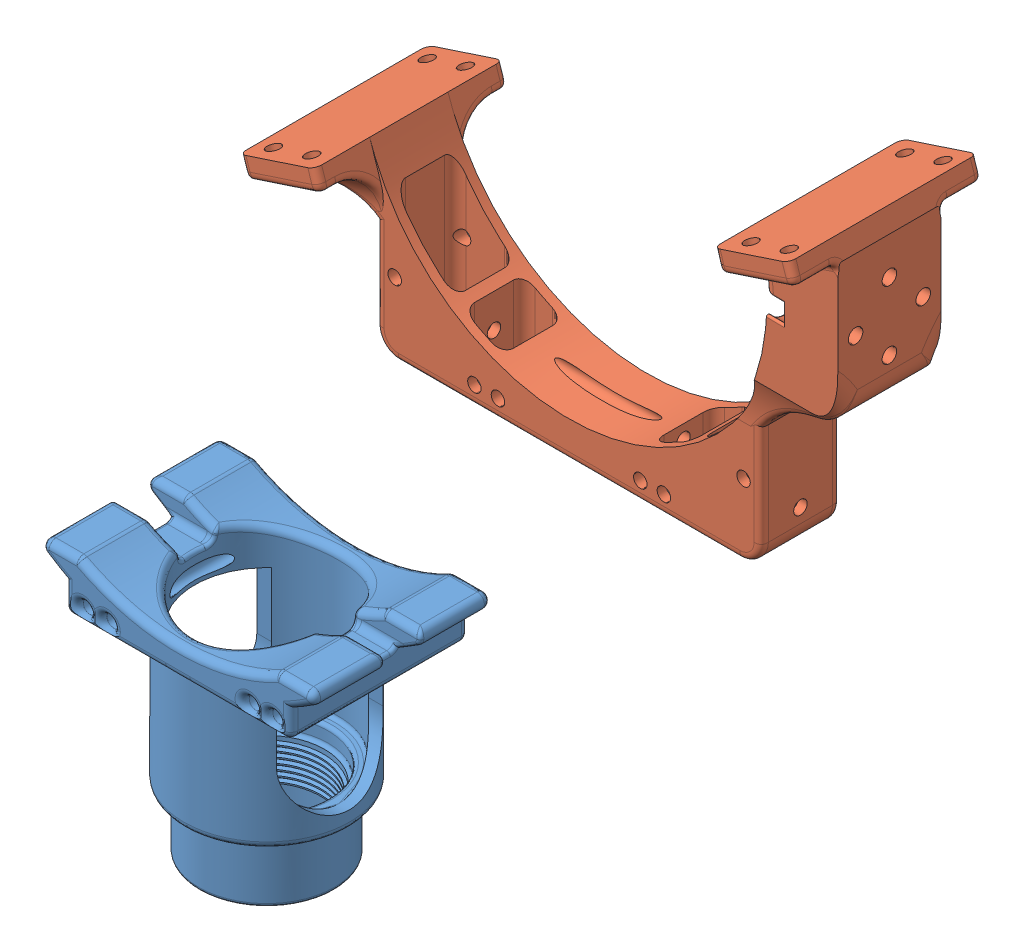
SolidWorks assembly transducer_holder_assembly, configuration Default. Lengths in mm.
Overall size (157.6 147.4 147.64).
2 component instances, 2 part files, 3 mates.
Components (placement in the parent):
- transducer_holder-1: transducer_holder [Default] at (-18.5558 -63.2327 11.3085) size (76.36 70 50.18)
- Motor Tube Mount - reduced-1: Motor Tube Mount - reduced [Default] at (-18.5558 58.7673 -84.6915) x (1 0 0) z (0 0 -1) size (157.6 94.45 53.1)
Mates (geometry in assembly coordinates):
- Concentric1: concentric: circle of transducer_holder-1; circle of Motor Tube Mount - reduced-1
- Parallel1: parallel aligned: plane of transducer_holder-1 through (-18.5558 -46.2327 11.3085) normal (0 -1 0); plane of Motor Tube Mount - reduced-1 through (-72.5558 -10.2327 39.7305) normal (0 -1 0)
- Distance1: distance = 85 mm aligned: plane of transducer_holder-1 through (-18.5558 -63.2327 11.3085) normal (0 0 1); plane of Motor Tube Mount - reduced-1 through (-18.5558 58.7673 -73.6915) normal (0 0 1)
